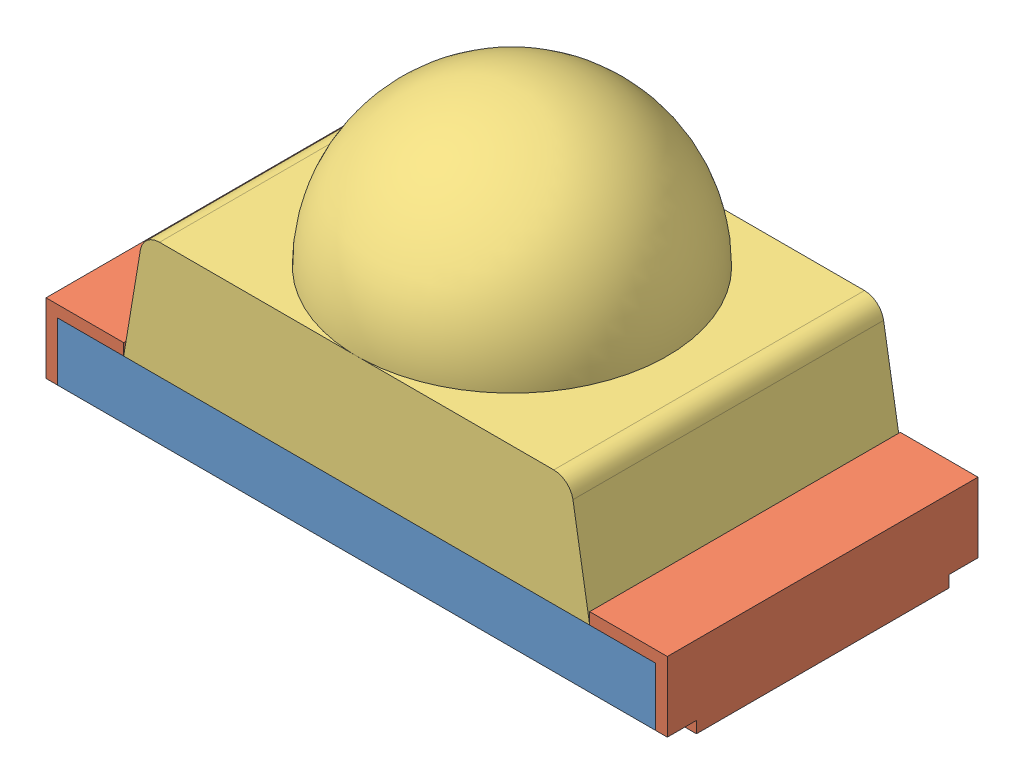
SolidWorks assembly LED0603B, configuration Default. Lengths in mm.
Overall size (1.6 0.88 0.8).
4 component instances, 3 part files, 9 mates.
Components (placement in the parent):
- LED0603-substrate-1: LED0603-substrate [Default] at (0 0.03 0) size (1.54 0.15 0.8)
- LED0603-clip-1: LED0603-clip [Default] at (-0.8 0.105 0) x (1 0 0) z (0 1 0) size (0.3 0.8 0.21)
- LED0603-clip-2: LED0603-clip [Default] at (0.8 0.105 0) x (-1 0 0) z (0 1 0) size (0.3 0.8 0.21)
- LED0603-lens-1: LED0603-lens [Default] at (0 0.18 0) size (1.2 0.7 0.8)
Mates (geometry in assembly coordinates):
- Coincident1: coincident aligned: plane of LED0603-substrate-1 through (0 0.03 0) normal (1 0 0)
- Coincident2: coincident aligned: plane of LED0603-substrate-1 through (0 0.03 0) normal (0 0 1)
- Distance1: distance = 0.03 mm aligned: plane of LED0603-substrate-1 through (0 0.03 0) normal (0 1 0)
- Coincident4: coincident anti-aligned: plane of LED0603-clip-1 through (-0.8 0.105 0) normal (0 0 -1)
- Coincident5: coincident anti-aligned: plane of LED0603-substrate-1 through (0 0.03 0) normal (0 -1 0); plane of LED0603-clip-1 through (-0.5 0.03 -0.4) normal (0 1 0)
- Coincident6: coincident anti-aligned: plane of LED0603-substrate-1 through (-0.77 0.18 0.4) normal (-1 0 0); plane of LED0603-clip-1 through (-0.77 0.18 -0.4) normal (1 0 0)
- Coincident7: coincident aligned: plane of LED0603-lens-1 through (0 0.18 0) normal (0 0 1)
- Coincident8: coincident aligned: plane of LED0603-lens-1 through (0 0.18 0) normal (1 0 0)
- Coincident9: coincident anti-aligned: plane of LED0603-substrate-1 through (0 0.18 0) normal (0 1 0); plane of LED0603-lens-1 through (0 0.18 0) normal (0 -1 0)
